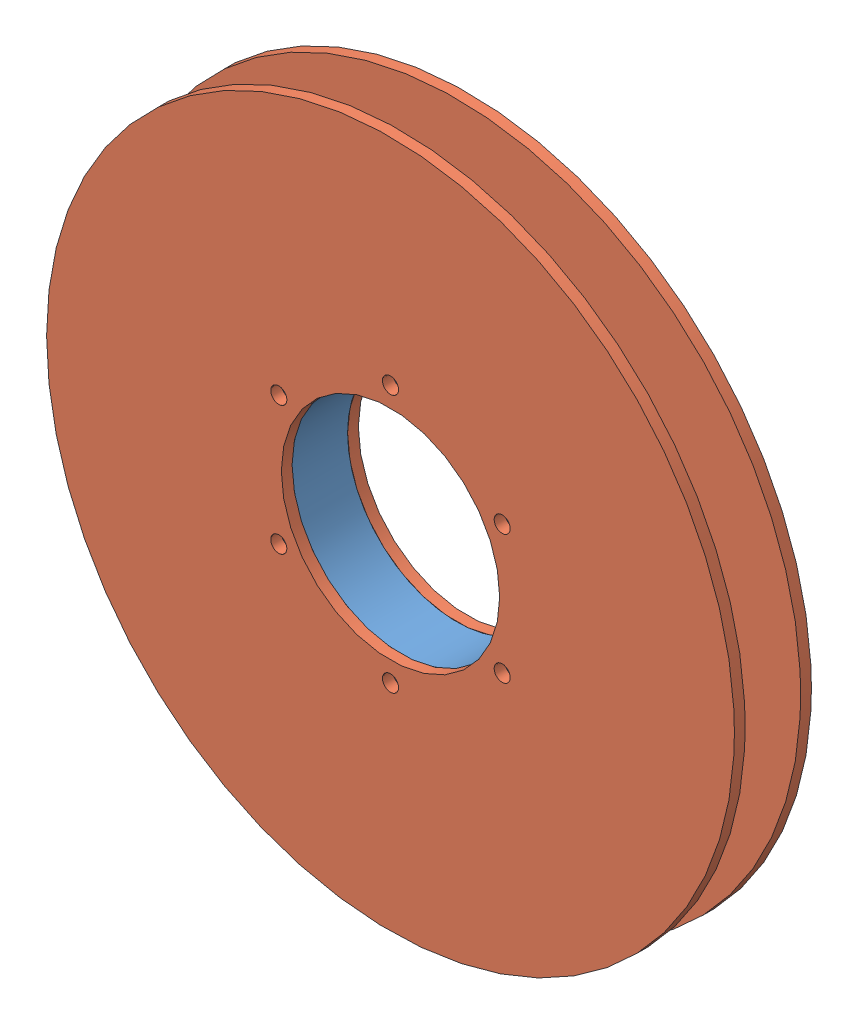
SolidWorks assembly reel, configuration Default. Lengths in mm.
Overall size (101.6 101.6 11.38).
3 component instances, 2 part files, 6 mates.
Components (placement in the parent):
- reel_hub-1: reel_hub [Default] at (2.2729 1.7407 -2.382) size (44.45 44.45 8.2)
- reel_wall-1: reel_wall [Default] at (2.2729 1.7407 5.818) size (101.6 101.6 1.59)
- reel_wall-2: reel_wall [Default] at (2.2729 1.7407 -3.9695) size (101.6 101.6 1.59)
Mates (geometry in assembly coordinates):
- Concentric1: concentric aligned: cylinder of reel_hub-1 through (2.2729 1.7407 5.818) axis (0 0 -1) radius 16.129; cylinder of reel_wall-1 through (2.2729 1.7407 7.4055) axis (0 0 -1) radius 16.129
- Concentric2: concentric aligned: cylinder of reel_hub-1 through (2.2729 1.7407 5.818) axis (0 0 -1) radius 16.129; cylinder of reel_wall-2 through (2.2729 1.7407 -2.382) axis (0 0 -1) radius 16.129
- Coincident1: coincident anti-aligned: plane of reel_hub-1 through (2.2729 1.7407 5.818) normal (0 0 1); plane of reel_wall-1 through (2.2729 1.7407 5.818) normal (0 0 -1)
- Coincident2: coincident anti-aligned: plane of reel_hub-1 through (2.2729 1.7407 -2.382) normal (0 0 -1); plane of reel_wall-2 through (2.2729 1.7407 -2.382) normal (0 0 1)
- Concentric3: concentric aligned: cylinder of reel_hub-1 through (18.7707 -7.7843 5.818) axis (0 0 1) radius 1.1906; cylinder of reel_wall-2 through (18.7707 -7.7843 -2.382) axis (0 0 1) radius 1.1906
- Coincident3: coincident aligned: cylinder of reel_hub-1 through (18.7707 11.2657 5.818) axis (0 0 1) radius 1.1906; circle of reel_wall-1
